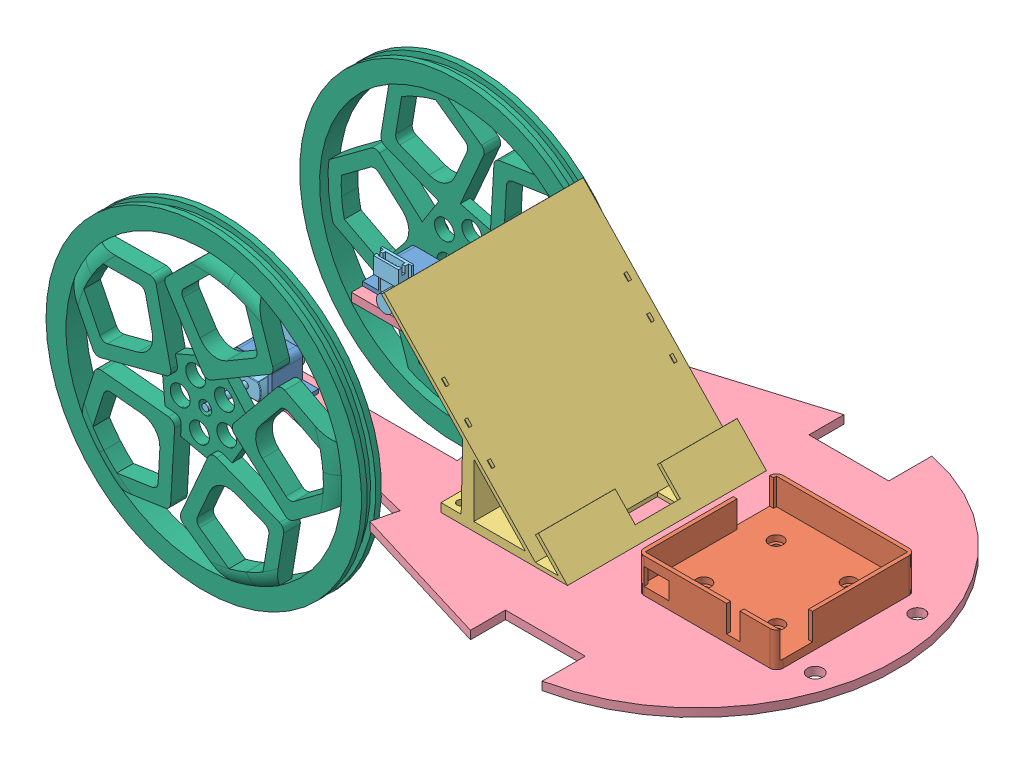
SolidWorks assembly FinalAssembly, configuration Default. Lengths in mm.
Overall size (291.88 157.99 149.32).
11 component instances, 7 part files, 26 mates.
Components (placement in the parent):
- MotorMount-1: MotorMount [Default] at (-178.8832 -24.172 243.3863) size (27.28 11.52 11.76)
- PCBHolder-1: PCBHolder [Default] at (1.8814 -22.394 277.3279) size (53.29 13.21 53.29)
- PhoneHolder-1: PhoneHolder [Default] at (-52.4807 -13.4909 315.3064) x (-1 0 0) z (0 0 -1) size (71.28 62.09 76.2)
- RobotBody-1: RobotBody [Default] at (-28.5866 -27.347 277.2064) size (226.5 3.17 149.32)
- MotorMount-2: MotorMount [Default] at (-178.8832 -24.172 299.2663) size (27.28 11.52 11.76)
- Motor-2: Motor [Default] at (-165.2688 -20.7955 249.3582) x (0 -1 0) z (1 0 0) size (16.87 34.95 11.99)
- Motor-3: Motor [Default] at (-165.218 -20.7955 305.0545) x (0 -1 0) z (-1 0 0) size (16.87 34.95 11.99)
- wheelV2-1: wheelV2 [Default] at (-153.8883 -25.9732 347.587) x (1 0 0) z (0 -1 0) (suppressed, hidden)
- wheelV2-2: wheelV2 [Default] at (-153.9391 -25.9732 251.4988) x (1 0 0) z (0 1 0) (suppressed, hidden)
- wheel-1: wheel [Default] at (-165.2688 -20.7955 225.3523) x (-0.923728 -0.383049 0) z (0.383049 -0.923728 0) size (120.9 10.57 120.9)
- wheel-2: wheel [Default] at (-165.218 -20.7955 329.0605) x (-0.923728 -0.383049 0) z (-0.383049 0.923728 0) size (120.9 10.57 120.9)
Mates (geometry in assembly coordinates):
- Lock1: lock: unknown of MotorMount-1; unknown of RobotBody-1
- Parallel1: parallel aligned: cylinder of MotorMount-1 through (-143.3219 -23.4416 271.6029) axis (0 -1 0) radius 1.55; cylinder of RobotBody-1 through (-143.4235 -29.3497 271.6029) axis (0 -1 0) radius 1.55
- Concentric3: concentric aligned: cylinder of RobotBody-1 through (-164.5055 -29.3497 327.4829) axis (0 -1 0) radius 1.55; cylinder of MotorMount-2 through (-164.5055 -23.4416 327.4829) axis (0 -1 0) radius 1.55
- Parallel2: parallel aligned: cylinder of RobotBody-1 through (-143.4235 -29.3497 327.4829) axis (0 -1 0) radius 1.55; cylinder of MotorMount-2 through (-143.3219 -23.4416 327.4829) axis (0 -1 0) radius 1.55
- Lock2: lock: unknown of PCBHolder-1; unknown of RobotBody-1
- Coincident5: coincident anti-aligned: plane of RobotBody-1 through (-17.2569 -29.3497 299.5429) normal (0 1 0); plane of MotorMount-2 through (-167.5535 -29.3497 333.363) normal (0 -1 0)
- Coincident10: coincident anti-aligned: plane of PhoneHolder-1 through (-41.151 -29.3497 261.4429) normal (0 -1 0); plane of RobotBody-1 through (-17.2569 -29.3497 299.5429) normal (0 1 0)
- Concentric11: concentric anti-aligned: cylinder of PhoneHolder-1 through (-36.8211 -33.7337 276.1749) axis (0 1 0) radius 1.55; cylinder of RobotBody-1 through (-36.8211 -29.3497 276.1749) axis (0 -1 0) radius 1.55
- Concentric12: concentric anti-aligned: cylinder of PhoneHolder-1 through (-36.8211 -33.7337 322.9109) axis (0 1 0) radius 1.55; cylinder of RobotBody-1 through (-36.8211 -29.3497 322.9109) axis (0 -1 0) radius 1.55
- Coincident11: coincident anti-aligned: plane of RobotBody-1 through (-17.2569 -29.3497 299.5429) normal (0 1 0); plane of Motor-2 through (-153.9391 -29.3497 252.6827) normal (0 -1 0)
- Parallel8: parallel aligned: plane of RobotBody-1 through (-17.2569 -29.3497 268.1357) normal (0 0 -1); plane of Motor-2 through (-153.9391 -25.9732 262.9288) normal (0 0 -1)
- Parallel9: parallel aligned: plane of MotorMount-1 through (-167.5535 -29.3497 265.7228) normal (0 0 -1); plane of Motor-2 through (-153.9391 -25.9732 262.9288) normal (0 0 -1)
- Coincident22: coincident anti-aligned: plane of RobotBody-1 through (-17.2569 -29.3497 299.5429) normal (0 1 0); plane of Motor-3 through (-153.8883 -29.3497 346.4031) normal (0 -1 0)
- Parallel11: parallel aligned: plane of MotorMount-2 through (-167.5535 -29.3497 333.363) normal (0 0 1); plane of Motor-3 through (-153.8883 -25.9732 336.157) normal (0 0 1)
- Tangent2: tangent anti-aligned: plane of MotorMount-2 through (-147.8939 -19.3548 333.363) normal (-1 0 0); cylinder of Motor-3 through (-153.8883 -25.9732 335.0823) axis (0 0 1) radius 5.9944
- Coincident24: coincident anti-aligned: plane of MotorMount-2 through (-167.5535 -29.3497 321.6028) normal (0 0 -1); plane of Motor-3 through (-153.8883 -25.9732 321.6028) normal (0 0 1)
- Tangent3: tangent anti-aligned: plane of MotorMount-1 through (-159.9335 -29.3497 277.483) normal (1 0 0); cylinder of Motor-2 through (-153.9391 -25.9732 264.0035) axis (0 0 -1) radius 5.9944
- Coincident27: coincident anti-aligned: plane of MotorMount-1 through (-167.5535 -29.3497 277.483) normal (0 0 1); plane of Motor-2 through (-153.9391 -25.9732 277.483) normal (0 0 -1)
- Concentric14: concentric: cylinder of Motor-3 through (-162.0975 -20.1481 335.0823) axis (0 0 1) radius 1.27; cylinder of wheelV2-1 through (-162.0975 -20.1481 351.397) axis (0 0 -1) radius 2.54
- Coincident28: coincident aligned: plane of Motor-3 through (-162.0975 -20.1481 351.397) normal (0 0 1); plane of wheelV2-1 through (-162.0975 -20.1481 351.397) normal (0 0 1)
- Concentric15: concentric: cylinder of Motor-2 through (-153.9391 -25.9732 264.0035) axis (0 0 -1) radius 1.27; cylinder of wheelV2-2 through (-153.9391 -25.9732 247.6888) axis (0 0 1) radius 2.54
- Coincident29: coincident aligned: circle of Motor-2; plane of wheelV2-2 through (-153.9391 -25.9732 247.6888) normal (0 0 -1)
- Concentric16: concentric: cylinder of Motor-2 through (-153.9391 -25.9732 264.0035) axis (0 0 -1) radius 1.27; cylinder of wheel-1 through (-153.9391 -25.9732 297.9657) axis (0 0 -1) radius 2.4892
- Coincident30: coincident aligned: plane of Motor-2 through (-153.9391 -25.9732 247.6888) normal (0 0 -1); plane of wheel-1 through (-153.9391 -25.9732 247.6888) normal (0 0 -1)
- Concentric17: concentric: cylinder of Motor-3 through (-165.218 -20.7955 312.7458) axis (0 0 1) radius 1.27; cylinder of wheel-2 through (-165.218 -20.7955 278.7836) axis (0 0 1) radius 2.4892
- Coincident31: coincident aligned: plane of Motor-3 through (-165.218 -20.7955 329.0605) normal (0 0 1); plane of wheel-2 through (-165.218 -20.7955 329.0605) normal (0 0 1)
